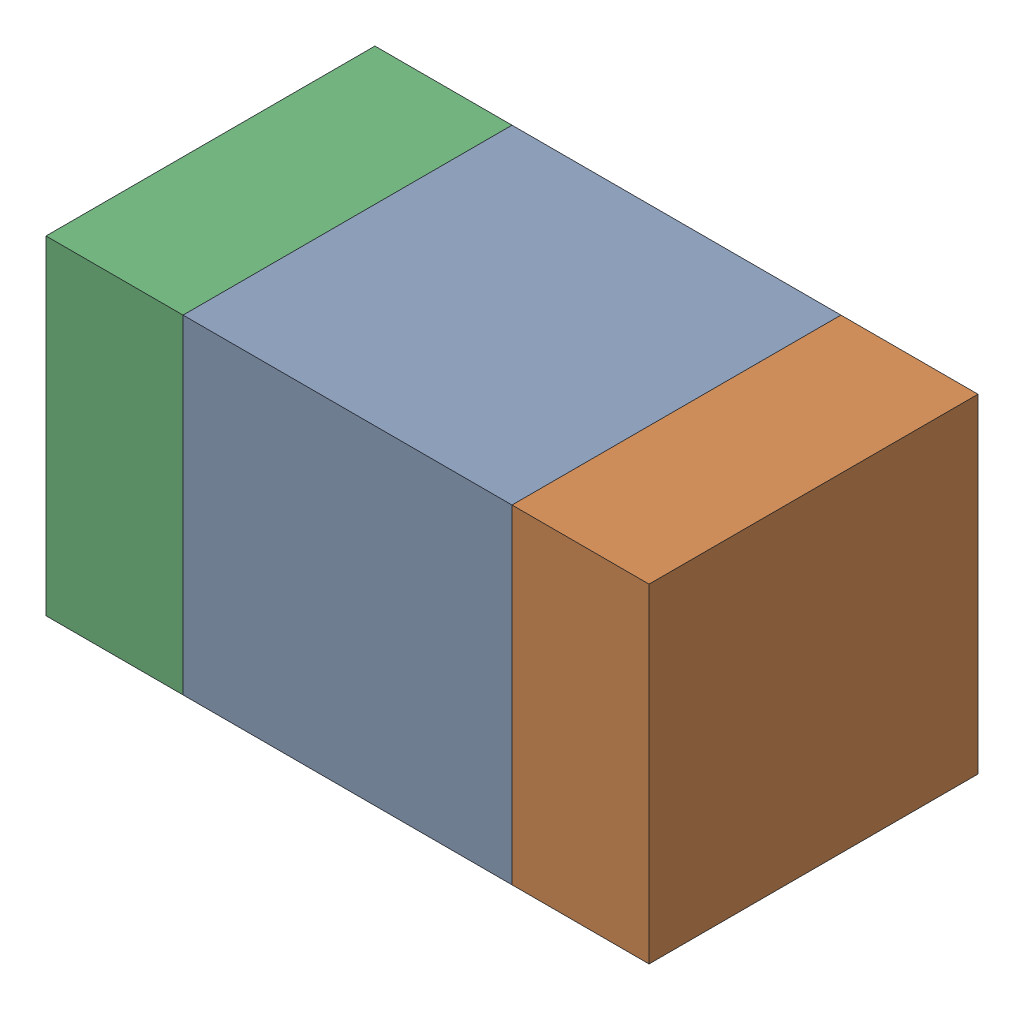
SolidWorks assembly C408PCB, configuration Default. Lengths in mm.
Overall size (1.1 0.6 0.6).
6 component instances, 2 part files, 0 mates.
Components (placement in the parent):
- 761606048-1: 761606048 [Default] at (88.29 86.7 0) size (0.6 0.6 0.6)
  - Extruded_9-1: Extruded_9 [Default] at origin size (0.6 0.6 0.6)
- 854785160-1: 854785160 [Default] at (88.715 86.7 0) size (0.25 0.6 0.6)
  - Extruded_19-1: Extruded_19 [Default] at origin size (0.25 0.6 0.6)
- 854785160-2: 854785160 [Default] at (87.865 86.7 0) size (0.25 0.6 0.6)
  - Extruded_19-1: Extruded_19 [Default] at origin size (0.25 0.6 0.6)
